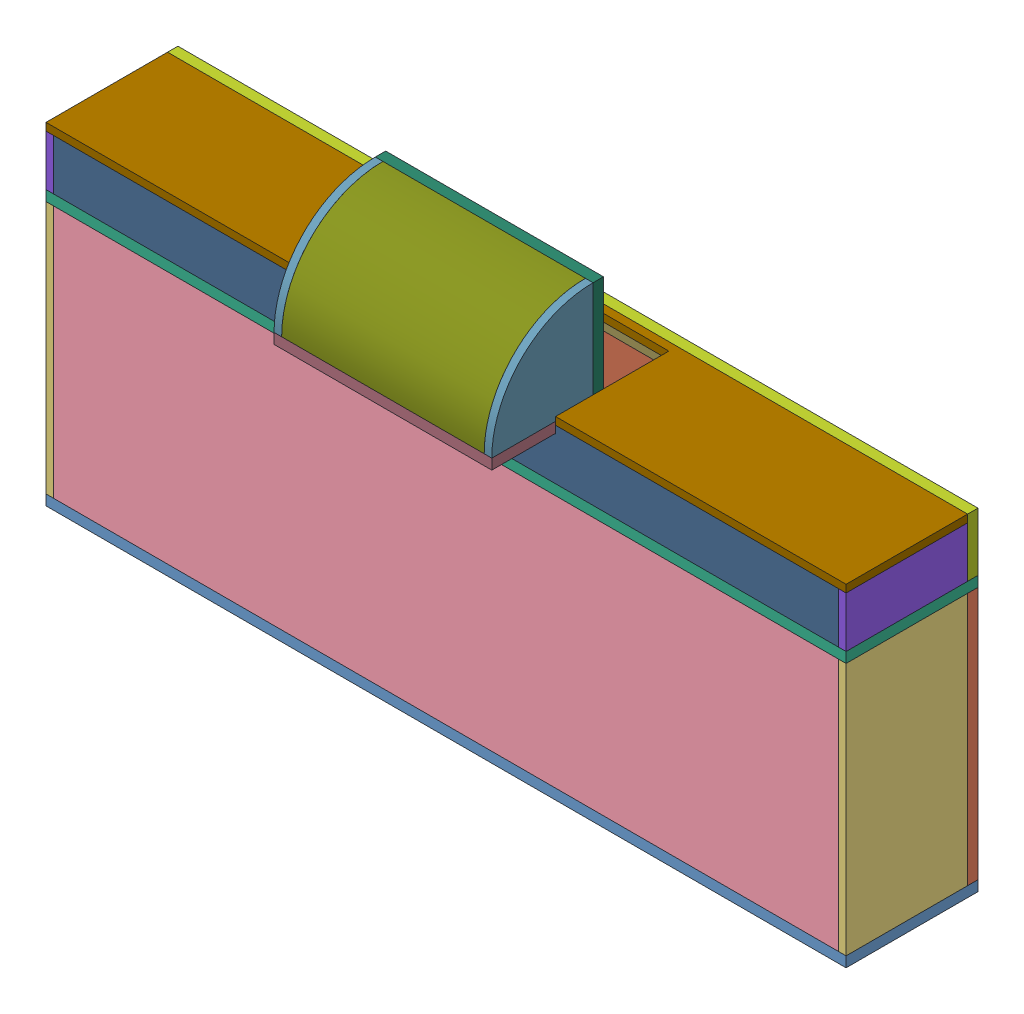
SolidWorks assembly omhulsel alles, configuration Default. Lengths in mm.
Overall size (316 169.3 77.03).
23 component instances, 16 part files, 5 mates.
Components (placement in the parent):
- omhulsel grot en afschiet-1: omhulsel grot en afschiet [Default] at (78.6007 7.9464 -47.9462) size (316 107.1 52.1)
  - onderstuk grot en afschiet-2: onderstuk grot en afschiet [Default] at (30.6252 101.7482 299.0234) size (316 4.3 52.1)
  - achterkant grot en afschiet-2: achterkant grot en afschiet [Default] at (30.6252 151.7482 277.0734) x (1 0 0) z (0 -1 0) size (316 4.3 100)
  - doorzichtig zijkant grot en afschiet-1: doorzichtig zijkant grot en afschiet [Default] at (-124.3748 151.7482 301.0734) x (0 0 1) z (0 -1 0) size (48 3 100)
  - doorzichtig zijkant grot en afschiet-2: doorzichtig zijkant grot en afschiet [Default] at (188.6252 151.7482 301.0734) x (0 0 1) z (0 -1 0) size (48 3 100)
  - doorzichtig voorkant grot en afschiet-1: doorzichtig voorkant grot en afschiet [Default] at (30.6252 151.7482 322.0734) x (1 0 0) z (0 -1 0) size (310 3 100)
  - plaatje 6 x15 x 3 grot en afschiet-1: plaatje 6 x15 x 3 grot en afschiet [Default] at (-121.3748 201.7482 298.7734) x (0 1 0) z (0 0 1) size (6 3 15)
  - plaatje 6 x15 x 3 grot en afschiet-2: plaatje 6 x15 x 3 grot en afschiet [Default] at (182.6252 201.7482 298.7734) x (0 -1 0) z (0 0 1) size (6 3 15)
- racebaan omhulsel-1: racebaan omhulsel [Default] at (-16.7772 69.2675 -2.4026) size (316 27.1 52.1)
  - onderstuk racebaan-1: onderstuk racebaan [Default] at (126.0031 144.5271 253.4798) size (316 4.3 52.1)
  - zijkant racebaan-1: zijkant racebaan [Default] at (126.0031 156.0271 231.5298) x (1 0 0) z (0 -1 0) size (316 4.3 23)
  - doorzichtig zijkant racebaan-1: doorzichtig zijkant racebaan [Default] at (-31.9969 154.5271 255.5298) x (0 0 1) z (0 1 0) size (48 3 20)
  - doorzichtig zijkant racebaan-2: doorzichtig zijkant racebaan [Default] at (284.0031 154.5271 255.5298) x (0 0 1) z (0 -1 0) size (48 3 20)
  - bovenstuk racebaan-3: bovenstuk racebaan [Default] at (126.0031 164.5271 255.5298) size (316 3 48)
  - doorzichtig voorkant racebaan-1: doorzichtig voorkant racebaan [Default] at (126.0031 154.5271 276.5298) x (1 0 0) z (0 -1 0) size (310 3 20)
  - plaatje racebaan-1: plaatje racebaan [Default] at (125.7531 158.5271 251.5298) size (92.5 3 40)
  - stukje plaat op plaat racebaan-1: stukje plaat op plaat racebaan [Default] at (125.104 161.5271 252.0658) size (92.5 3 40)
- omhulsel auto logo-1: omhulsel auto logo [Default] at (69.2794 191.304 216.2051) size (86 44.1 44.1)
  - logo hotwheels onderstuk-1: logo hotwheels onderstuk [Default] at (39.9465 43.5906 63.8014) size (86 4.3 44.1)
  - ronde zijkant-1: ronde zijkant [Default] at (79.9465 43.5906 85.8514) size (3 40 40)
  - ronde zijkant-2: ronde zijkant [Default] at (-3.0535 43.5906 85.8514) size (3 40 40)
  - logo hotwheels zijkant-1: logo hotwheels zijkant [Default] at (39.9465 63.5906 45.8514) x (1 0 0) z (0 -1 0) size (86 4.3 40)
  - zijkant krom-1: zijkant krom [Default] at (39.9465 43.5904 45.8512) size (80 40 40)
Mates (geometry in assembly coordinates):
- Coincident1: coincident: plane of omhulsel grot en afschiet-1/achterkant grot en afschiet-2 through (109.2259 159.6946 225.0272) normal (0 0 -1); plane of racebaan omhulsel-1/zijkant racebaan-1 through (109.2259 225.2946 225.0272) normal (0 0 -1)
- Coincident2: coincident: plane of omhulsel grot en afschiet-1/achterkant grot en afschiet-2 through (-48.7741 109.6946 225.0272) normal (-1 0 0); plane of racebaan omhulsel-1/onderstuk racebaan-1 through (-48.7741 209.6946 277.1272) normal (-1 0 0)
- Coincident3: coincident: plane of omhulsel grot en afschiet-1/achterkant grot en afschiet-2 through (267.2259 209.6946 225.0272) normal (0 1 0); plane of racebaan omhulsel-1/onderstuk racebaan-1 through (109.2259 209.6946 251.0772) normal (0 -1 0)
- Coincident4: coincident: plane of racebaan omhulsel-1/plaatje racebaan-1 through (108.9759 230.7946 249.1272) normal (0 1 0); plane of omhulsel auto logo-1/logo hotwheels onderstuk-1 through (109.7259 230.7946 280.0065) normal (0 -1 0)
- Distance1: distance = 0.25 mm: plane of omhulsel auto logo-1/logo hotwheels onderstuk-1 through (152.2259 230.7946 302.0565) normal (1 0 0); plane of racebaan omhulsel-1/bovenstuk racebaan-3 through (152.4759 236.7946 232.3772) normal (-1 0 0)
